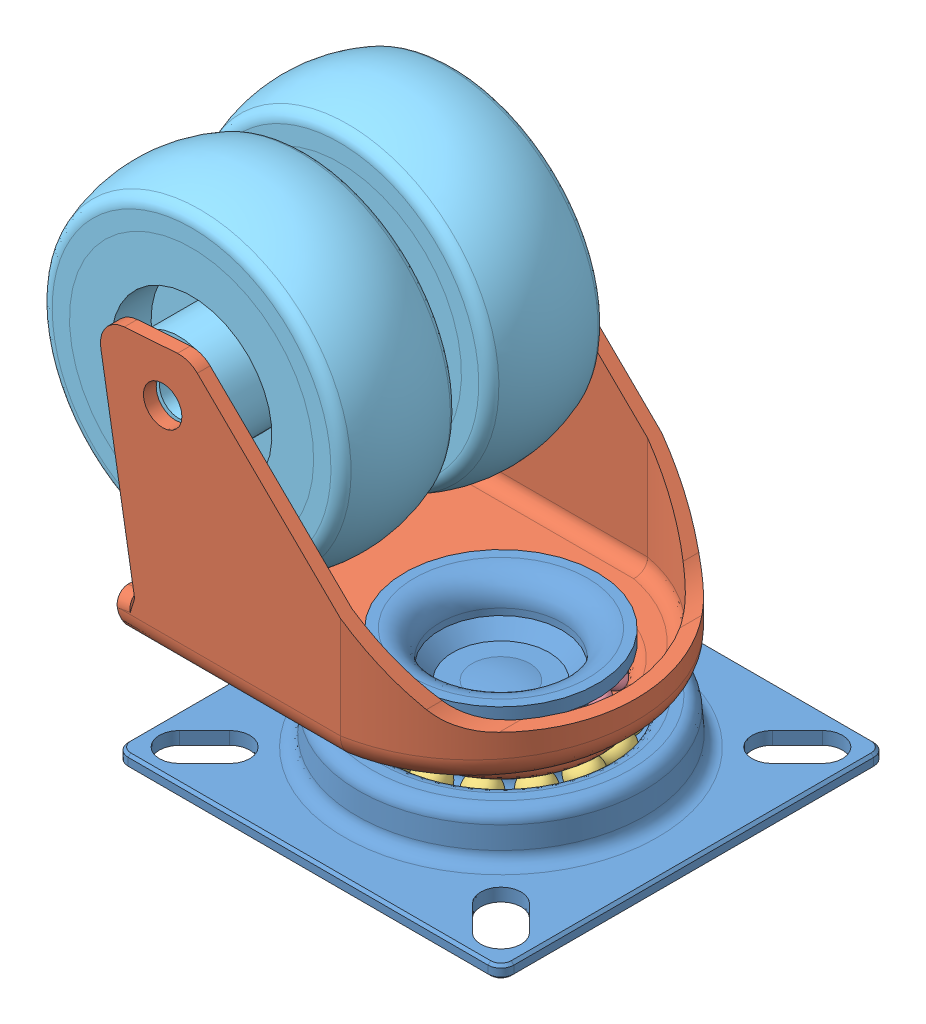
SolidWorks assembly Double_Wheel_Caster, configuration Défaut. Lengths in mm.
Overall size (86.95 76.01 60).
40 component instances, 7 part files, 12 mates.
Components (placement in the parent):
- Base_Double_Wheel_Caster-1: Base_Double_Wheel_Caster [Défaut] at (-86.2482 -35.3082 0) size (60 18 60)
- Top_Double_Wheel_Caster-1: Top_Double_Wheel_Caster [Défaut] at (-86.2482 -24.3082 0) size (58.32 46.89 50)
- 5mm_Ball_Double_Wheel_Caster-1: 5mm_Ball_Double_Wheel_Caster [Défaut] at (-95.1439 -30.8082 10.2872) x (0.991423 0 0.130689) z (-0.130689 0 0.991423) size (5 5 5)
- 3mm_Ball_Double_Wheel_Caster-1: 3mm_Ball_Double_Wheel_Caster [Défaut] at (-95.742 -22.3082 -9.0265) x (0.875718 0.080159 -0.476122) z (0.482394 -0.103717 0.869793) size (3 3 3)
- 3mm_Ball_Double_Wheel_Caster-2: 3mm_Ball_Double_Wheel_Caster [Défaut] at (-92.488 -22.3082 -11.5185) x (0.979987 0.080159 -0.182207) z (0.190003 -0.103717 0.97629) size (3 3 3)
- 3mm_Ball_Double_Wheel_Caster-3: 3mm_Ball_Double_Wheel_Caster [Défaut] at (-88.6232 -22.3082 -12.8829) x (0.988328 0.080159 0.129544) z (-0.120987 -0.103717 0.987221) size (3 3 3)
- 3mm_Ball_Double_Wheel_Caster-4: 3mm_Ball_Double_Wheel_Caster [Défaut] at (-84.5259 -22.3082 -12.9863) x (0.899925 0.080159 0.428614) z (-0.420133 -0.103717 0.901516) size (3 3 3)
- 3mm_Ball_Double_Wheel_Caster-5: 3mm_Ball_Double_Wheel_Caster [Défaut] at (-80.5972 -22.3082 -11.8185) x (0.72343 0.080159 0.685728) z (-0.678154 -0.103717 0.727564) size (3 3 3)
- 3mm_Ball_Double_Wheel_Caster-6: 3mm_Ball_Double_Wheel_Caster [Défaut] at (-77.2217 -22.3082 -9.4938) x (0.476122 0.080159 0.875718) z (-0.869793 -0.103717 0.482394) size (3 3 3)
- 3mm_Ball_Double_Wheel_Caster-7: 3mm_Ball_Double_Wheel_Caster [Défaut] at (-74.7297 -22.3082 -6.2398) x (0.182207 0.080159 0.979987) z (-0.97629 -0.103717 0.190003) size (3 3 3)
- 3mm_Ball_Double_Wheel_Caster-8: 3mm_Ball_Double_Wheel_Caster [Défaut] at (-73.3653 -22.3082 -2.375) x (-0.129544 0.080159 0.988328) z (-0.987221 -0.103717 -0.120987) size (3 3 3)
- 3mm_Ball_Double_Wheel_Caster-9: 3mm_Ball_Double_Wheel_Caster [Défaut] at (-73.2619 -22.3082 1.7223) x (-0.428614 0.080159 0.899925) z (-0.901516 -0.103717 -0.420133) size (3 3 3)
- 3mm_Ball_Double_Wheel_Caster-10: 3mm_Ball_Double_Wheel_Caster [Défaut] at (-74.4297 -22.3082 5.651) x (-0.685728 0.080159 0.72343) z (-0.727564 -0.103717 -0.678154) size (3 3 3)
- 3mm_Ball_Double_Wheel_Caster-11: 3mm_Ball_Double_Wheel_Caster [Défaut] at (-76.7544 -22.3082 9.0265) x (-0.875718 0.080159 0.476122) z (-0.482394 -0.103717 -0.869793) size (3 3 3)
- 3mm_Ball_Double_Wheel_Caster-12: 3mm_Ball_Double_Wheel_Caster [Défaut] at (-80.0084 -22.3082 11.5185) x (-0.979987 0.080159 0.182207) z (-0.190003 -0.103717 -0.97629) size (3 3 3)
- 3mm_Ball_Double_Wheel_Caster-13: 3mm_Ball_Double_Wheel_Caster [Défaut] at (-83.8732 -22.3082 12.8829) x (-0.988328 0.080159 -0.129544) z (0.120987 -0.103717 -0.987221) size (3 3 3)
- 3mm_Ball_Double_Wheel_Caster-14: 3mm_Ball_Double_Wheel_Caster [Défaut] at (-87.9705 -22.3082 12.9863) x (-0.899925 0.080159 -0.428614) z (0.420133 -0.103717 -0.901516) size (3 3 3)
- 3mm_Ball_Double_Wheel_Caster-15: 3mm_Ball_Double_Wheel_Caster [Défaut] at (-91.8992 -22.3082 11.8185) x (-0.72343 0.080159 -0.685728) z (0.678154 -0.103717 -0.727564) size (3 3 3)
- 3mm_Ball_Double_Wheel_Caster-16: 3mm_Ball_Double_Wheel_Caster [Défaut] at (-95.2747 -22.3082 9.4938) x (-0.476122 0.080159 -0.875718) z (0.869793 -0.103717 -0.482394) size (3 3 3)
- 3mm_Ball_Double_Wheel_Caster-17: 3mm_Ball_Double_Wheel_Caster [Défaut] at (-97.7667 -22.3082 6.2398) x (-0.182207 0.080159 -0.979987) z (0.97629 -0.103717 -0.190003) size (3 3 3)
- 3mm_Ball_Double_Wheel_Caster-18: 3mm_Ball_Double_Wheel_Caster [Défaut] at (-99.1311 -22.3082 2.375) x (0.129544 0.080159 -0.988328) z (0.987221 -0.103717 0.120987) size (3 3 3)
- 3mm_Ball_Double_Wheel_Caster-19: 3mm_Ball_Double_Wheel_Caster [Défaut] at (-99.2345 -22.3082 -1.7223) x (0.428614 0.080159 -0.899925) z (0.901516 -0.103717 0.420133) size (3 3 3)
- 3mm_Ball_Double_Wheel_Caster-20: 3mm_Ball_Double_Wheel_Caster [Défaut] at (-98.0667 -22.3082 -5.651) x (0.685728 0.080159 -0.72343) z (0.727564 -0.103717 0.678154) size (3 3 3)
- 5mm_Ball_Double_Wheel_Caster-2: 5mm_Ball_Double_Wheel_Caster [Défaut] at (-98.7264 -30.8082 5.4088) x (0.836538 0 0.547909) z (-0.547909 0 0.836538) size (5 5 5)
- 5mm_Ball_Double_Wheel_Caster-3: 5mm_Ball_Double_Wheel_Caster [Défaut] at (-99.8374 -30.8082 -0.5409) x (0.515966 0 0.856609) z (-0.856609 0 0.515966) size (5 5 5)
- 5mm_Ball_Double_Wheel_Caster-4: 5mm_Ball_Double_Wheel_Caster [Défaut] at (-98.257 -30.8082 -6.3835) x (0.093201 0 0.995647) z (-0.995647 0 0.093201) size (5 5 5)
- 5mm_Ball_Double_Wheel_Caster-5: 5mm_Ball_Double_Wheel_Caster [Défaut] at (-94.298 -30.8082 -10.9618) x (-0.348024 0 0.937485) z (-0.937485 0 -0.348024) size (5 5 5)
- 5mm_Ball_Double_Wheel_Caster-6: 5mm_Ball_Double_Wheel_Caster [Défaut] at (-88.7447 -30.8082 -13.3689) x (-0.720319 0 0.693643) z (-0.693643 0 -0.720319) size (5 5 5)
- 5mm_Ball_Double_Wheel_Caster-7: 5mm_Ball_Double_Wheel_Caster [Défaut] at (-82.6969 -30.8082 -13.1282) x (-0.949945 0 0.312416) z (-0.312416 0 -0.949945) size (5 5 5)
- 5mm_Ball_Double_Wheel_Caster-8: 5mm_Ball_Double_Wheel_Caster [Défaut] at (-77.3525 -30.8082 -10.2872) x (-0.991423 0 -0.130689) z (0.130689 0 -0.991423) size (5 5 5)
- 5mm_Ball_Double_Wheel_Caster-9: 5mm_Ball_Double_Wheel_Caster [Défaut] at (-73.77 -30.8082 -5.4088) x (-0.836538 0 -0.547909) z (0.547909 0 -0.836538) size (5 5 5)
- 5mm_Ball_Double_Wheel_Caster-10: 5mm_Ball_Double_Wheel_Caster [Défaut] at (-72.659 -30.8082 0.5409) x (-0.515966 0 -0.856609) z (0.856609 0 -0.515966) size (5 5 5)
- 5mm_Ball_Double_Wheel_Caster-11: 5mm_Ball_Double_Wheel_Caster [Défaut] at (-74.2394 -30.8082 6.3835) x (-0.093201 0 -0.995647) z (0.995647 0 -0.093201) size (5 5 5)
- 5mm_Ball_Double_Wheel_Caster-12: 5mm_Ball_Double_Wheel_Caster [Défaut] at (-78.1984 -30.8082 10.9618) x (0.348024 0 -0.937485) z (0.937485 0 0.348024) size (5 5 5)
- 5mm_Ball_Double_Wheel_Caster-13: 5mm_Ball_Double_Wheel_Caster [Défaut] at (-83.7517 -30.8082 13.3689) x (0.720319 0 -0.693643) z (0.693643 0 0.720319) size (5 5 5)
- 5mm_Ball_Double_Wheel_Caster-14: 5mm_Ball_Double_Wheel_Caster [Défaut] at (-89.7995 -30.8082 13.1282) x (0.949945 0 -0.312416) z (0.312416 0 0.949945) size (5 5 5)
- Wheel_Double_Wheel_Caster-1: Wheel_Double_Wheel_Caster [Défaut] at (-113.8861 10.389 -11.5) x (0 0 1) z (-0.986683 -0.162657 0) size (22 50 50)
- Wheel_Double_Wheel_Caster-2: Wheel_Double_Wheel_Caster [Défaut] at (-113.8861 10.389 11.5) x (0 0 1) z (-0.981648 -0.190702 0) size (22 50 50)
- hex bolt gradeb_iso-1: hex bolt gradeb_iso [ISO 4015 - M6 x 60 x 18-S] at (-113.8861 10.389 -29) x (0 0 1) z (-1 0 0) (suppressed, hidden)
- hex nut gradec_iso-1: hex nut gradec_iso [Hexagon Nut ISO - 4034 - M6 - S] at (-113.8861 10.389 31.1) (suppressed, hidden)
Mates (geometry in assembly coordinates):
- Coaxiale1: concentric anti-aligned: cylinder of Base_Double_Wheel_Caster-1 through (-86.2482 -35.3082 0) axis (0 -1 0) radius 9.5; cylinder of Top_Double_Wheel_Caster-1 through (-86.2482 -28.3092 0) axis (0 1 0) radius 9.5
- Distance1: distance = 3 mm anti-aligned: plane of Base_Double_Wheel_Caster-1 through (-66.1104 -27.3082 0) normal (0 1 0); plane of Top_Double_Wheel_Caster-1 through (-120.2482 -24.3082 25) normal (0 -1 0)
- Coïncidente3: coincident: circle of Base_Double_Wheel_Caster-1; point of 5mm_Ball_Double_Wheel_Caster-1
- Coïncidente4: coincident: circle of Base_Double_Wheel_Caster-1; point of 3mm_Ball_Double_Wheel_Caster-1
- Coaxiale2: concentric aligned: cylinder of Top_Double_Wheel_Caster-1 through (-113.8861 10.389 25) axis (0 0 -1) radius 3; cylinder of Wheel_Double_Wheel_Caster-1 through (-113.8861 10.389 -22.5) axis (0 0 -1) radius 3
- Distance2: distance = 0.5 mm anti-aligned: plane of Wheel_Double_Wheel_Caster-1 through (-115.2037 18.3811 -22.5) normal (0 0 -1); plane of Top_Double_Wheel_Caster-1 through (-86.2482 -24.3082 -23) normal (0 0 1)
- Coaxiale3: concentric aligned: cylinder of Top_Double_Wheel_Caster-1 through (-113.8861 10.389 25) axis (0 0 -1) radius 3; cylinder of Wheel_Double_Wheel_Caster-2 through (-113.8861 10.389 0.5) axis (0 0 -1) radius 3
- Distance3: distance = 0.5 mm anti-aligned: plane of Wheel_Double_Wheel_Caster-2 through (-114.4582 13.3339 22.5) normal (0 0 1); plane of Top_Double_Wheel_Caster-1 through (-86.2482 -24.3082 23) normal (0 0 -1)
- Coaxiale4: concentric: cylinder of Top_Double_Wheel_Caster-1 through (-113.8861 10.389 25) axis (0 0 -1) radius 3; cylinder of hex bolt gradeb_iso-1 through (-113.8861 10.389 -29) axis (0 0 -1) radius 3
- Coïncidente10: coincident: plane of Top_Double_Wheel_Caster-1 through (-86.2482 -24.3082 -25) normal (0 0 -1); plane of hex bolt gradeb_iso-1 through (-103.8861 10.389 -25) normal (0 0 1)
- Coaxiale61: concentric: cylinder of Top_Double_Wheel_Caster-1 through (-113.8861 10.389 25) axis (0 0 -1) radius 3; cylinder of hex nut gradec_iso-1 through (-113.8861 10.389 6.0625) axis (0 0 1) radius 3
- Coïncidente131: coincident: plane of Top_Double_Wheel_Caster-1 through (-86.2482 -24.3082 25) normal (0 0 1); plane of hex nut gradec_iso-1 through (-113.8861 16.1625 25) normal (0 0 -1)
